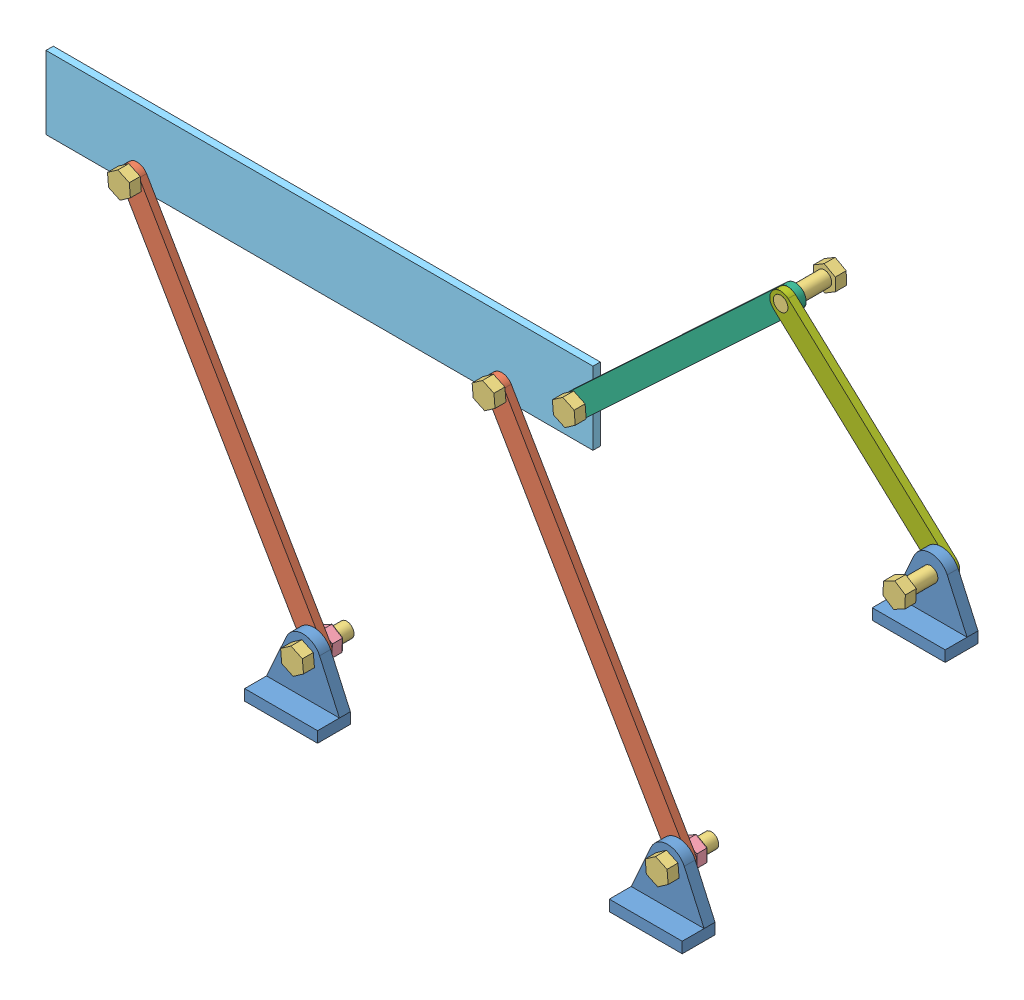
SolidWorks assembly 筛子, configuration 默认. Lengths in mm.
Overall size (259.58 165.17 28).
20 component instances, 7 part files, 39 mates.
Components (placement in the parent):
- 支座4-1: 支座4 [默认] at (-4.9178 3.6602 0) size (20 18 9)
- 杆100-1: 杆100 [默认] at (-31.141 48.5122 -2) x (-0.504726 0.86328 0) z (0 0 1) size (106 6 2)
- 螺钉4,12-1: 螺钉4,12 [默认] at (-4.9178 3.6602 3) size (6.28 6.9 15)
- 螺母4-1: 螺母4 [默认] at (-4.9178 3.6602 -2) x (-0.923728 -0.383049 0) z (0 0 -1) size (6.9 6.3 3)
- 支座4-2: 支座4 [默认] at (95.0822 3.6602 0) size (20 18 9)
- 螺钉4,12-2: 螺钉4,12 [默认] at (95.0822 3.6602 3) size (6.28 6.9 15)
- 螺母4-2: 螺母4 [默认] at (95.0822 3.6602 -2) x (-0.909504 -0.415695 0) z (0 0 -1) size (6.9 6.3 3)
- 杆100-2: 杆100 [默认] at (70.8328 45.1362 -2) x (0.504726 -0.86328 0) z (0 0 1) size (106 6 2)
- 平台-1: 平台 [默认] at (-5.3904 96.9882 -2) x (-1 0 0) z (0 0 -1) size (150 20 2)
- 螺钉4,12-3: 螺钉4,12 [默认] at (44.6096 89.9882 0) size (6.28 6.9 15)
- 螺母4-3: 螺母4 [默认] at (44.6096 89.9882 -4) x (0.120808 -0.992676 0) z (0 0 -1) size (6.9 6.3 3)
- 螺钉4,12-4: 螺钉4,12 [默认] at (-55.3904 89.9882 0) size (6.28 6.9 15)
- 螺母4-4: 螺母4 [默认] at (-55.3904 89.9882 -4) x (-0.923728 -0.383049 0) z (0 0 -1) size (6.9 6.3 3)
- 杆80-1: 杆80 [默认] at (98.5457 126.807 -2) x (0.73092 0.682463 0) z (0 0 1) size (86 6 2)
- 螺钉4,12-5: 螺钉4,12 [默认] at (66.6096 96.9882 0) size (6.28 6.9 15)
- 螺母4-5: 螺母4 [默认] at (66.6096 96.9882 -4) x (0.120808 -0.992676 0) z (0 0 -1) size (6.9 6.3 3)
- 杆60-1: 杆60 [默认] at (157.9979 121.2367 0) x (0.735185 -0.677867 0) z (0 0 1) size (66 6 2)
- 螺钉4,12-6: 螺钉4,12 [默认] at (125.0832 151.5852 -10) x (0.9945 0.104738 0) z (0 0 -1) size (6.28 6.9 15)
- 支座4-3: 支座4 [默认] at (169.1943 110.9132 2) size (20 18 9)
- 螺钉4,12-7: 螺钉4,12 [默认] at (169.1943 110.9132 12) x (0.990726 -0.135875 0) z (0 0 1) size (6.28 6.9 15)
Mates (geometry in assembly coordinates):
- 重合1: coincident: plane of 支座4-1 through (-4.9178 3.6602 0) normal (0 0 -1); plane of 杆100-1 through (-4.9178 3.6602 0) normal (0 0 1)
- 同心1: concentric: cylinder of 支座4-1 through (-4.9178 3.6602 3) axis (0 0 -1) radius 2; cylinder of 杆100-1 through (-4.9178 3.6602 0) axis (0 0 -1) radius 2
- 重合2: coincident: plane of 支座4-1 through (-4.9178 3.6602 3) normal (0 0 1); plane of 螺钉4,12-1 through (-4.6186 0.2091 3) normal (0 0 -1)
- 同心2: concentric: cylinder of 支座4-1 through (-4.9178 3.6602 3) axis (0 0 -1) radius 2; cylinder of 螺钉4,12-1 through (-4.9178 3.6602 -9) axis (0 0 1) radius 2
- 重合3: coincident: plane of 杆100-1 through (-4.9178 3.6602 -2) normal (0 0 -1); plane of 螺母4-1 through (-5.0386 0.1982 -2) normal (0 0 1)
- 同心3: concentric: cylinder of 螺钉4,12-1 through (-4.9178 3.6602 -9) axis (0 0 1) radius 2; cylinder of 螺母4-1 through (-4.9178 3.6602 -5) axis (0 0 1) radius 2
- 重合6: coincident: plane of 支座4-1; plane of 支座4-2
- 重合7: coincident: plane of 支座4-1 through (-4.9178 3.6602 0) normal (0 0 -1); plane of 支座4-2 through (95.0822 3.6602 0) normal (0 0 -1)
- 距离1: distance = 100 mm: plane of 支座4-1; plane of 支座4-2
- 重合9: coincident: plane of 支座4-2 through (95.0822 3.6602 3) normal (0 0 1); plane of 螺钉4,12-2 through (95.3814 0.2091 3) normal (0 0 -1)
- 同心4: concentric: cylinder of 支座4-2 through (95.0822 3.6602 3) axis (0 0 -1) radius 2; cylinder of 螺钉4,12-2 through (95.0822 3.6602 -9) axis (0 0 1) radius 2
- 重合10: coincident: plane of 支座4-2 through (95.0822 3.6602 0) normal (0 0 -1); plane of 杆100-2 through (108.528 102.7522 0) normal (0 0 1)
- 同心5: concentric: cylinder of 螺钉4,12-2 through (95.0822 3.6602 -9) axis (0 0 1) radius 2; cylinder of 杆100-2 through (95.0822 3.6602 0) axis (0 0 -1) radius 2
- 同心6: concentric: cylinder of 螺钉4,12-2 through (95.0822 3.6602 -9) axis (0 0 1) radius 2; cylinder of 螺母4-2 through (95.0822 3.6602 -5) axis (0 0 1) radius 2
- 重合12: coincident: plane of 杆100-1 through (-4.9178 3.6602 -2) normal (0 0 -1); plane of 平台-1 through (58.528 -8.0944 -2) normal (0 0 1)
- 同心9: concentric: cylinder of 杆100-2 through (108.528 102.7522 0) axis (0 0 -1) radius 2; cylinder of 螺钉4,12-3 through (108.528 102.7522 -12) axis (0 0 1) radius 2
- 重合13: coincident: plane of 杆100-2 through (108.528 102.7522 0) normal (0 0 1); plane of 螺钉4,12-3 through (108.8272 99.301 0) normal (0 0 -1)
- 同心10: concentric: cylinder of 平台-1 through (108.528 102.7522 -4) axis (0 0 1) radius 2; cylinder of 螺钉4,12-3 through (108.528 102.7522 -12) axis (0 0 1) radius 2
- 重合14: coincident: plane of 平台-1 through (58.528 -8.0944 -4) normal (0 0 -1); plane of 螺母4-3 through (111.8303 101.7057 -4) normal (0 0 1)
- 同心11: concentric: cylinder of 螺钉4,12-3 through (108.528 102.7522 -12) axis (0 0 1) radius 2; cylinder of 螺母4-3 through (108.528 102.7522 -7) axis (0 0 1) radius 2
- 重合15: coincident: plane of 杆100-1 through (-4.9178 3.6602 0) normal (0 0 1); plane of 螺钉4,12-4 through (8.8272 99.301 0) normal (0 0 -1)
- 同心12: concentric: cylinder of 杆100-1 through (8.528 102.7522 0) axis (0 0 -1) radius 2; cylinder of 螺钉4,12-4 through (8.528 102.7522 -12) axis (0 0 1) radius 2
- 同心13: concentric: cylinder of 平台-1 through (8.528 102.7522 -4) axis (0 0 1) radius 2; cylinder of 螺钉4,12-4 through (8.528 102.7522 -12) axis (0 0 1) radius 2
- 重合16: coincident: plane of 平台-1 through (58.528 -8.0944 -4) normal (0 0 -1); plane of 螺母4-4 through (8.4072 99.2902 -4) normal (0 0 1)
- 同心14: concentric: cylinder of 螺钉4,12-4 through (8.528 102.7522 -12) axis (0 0 1) radius 2; cylinder of 螺母4-4 through (8.528 102.7522 -7) axis (0 0 1) radius 2
- 重合17: coincident: plane of 平台-1 through (58.528 -8.0944 -2) normal (0 0 1); plane of 杆80-1 through (130.528 109.7522 -2) normal (0 0 -1)
- 重合18: coincident: plane of 杆80-1 through (130.528 109.7522 0) normal (0 0 1); plane of 螺钉4,12-5 through (130.8272 106.301 0) normal (0 0 -1)
- 同心15: concentric: cylinder of 杆80-1 through (130.528 109.7522 0) axis (0 0 -1) radius 2; cylinder of 螺钉4,12-5 through (130.528 109.7522 -12) axis (0 0 1) radius 2
- 同心16: concentric: cylinder of 平台-1 through (130.528 109.7522 -4) axis (0 0 1) radius 2; cylinder of 螺钉4,12-5 through (130.528 109.7522 -12) axis (0 0 1) radius 2
- 同心17: concentric: cylinder of 螺钉4,12-5 through (130.528 109.7522 -12) axis (0 0 1) radius 2; cylinder of 螺母4-5 through (130.528 109.7522 -7) axis (0 0 1) radius 2
- 重合19: coincident: plane of 平台-1 through (58.528 -8.0944 -4) normal (0 0 -1); plane of 螺母4-5 through (133.8303 108.7057 -4) normal (0 0 1)
- 同心18: concentric: cylinder of 杆80-1 through (184.64 168.6749 0) axis (0 0 -1) radius 2; cylinder of 螺钉4,12-6 through (184.64 168.6749 2) axis (0 0 -1) radius 2
- 同心19: concentric: cylinder of 杆60-1 through (184.64 168.6749 2) axis (0 0 -1) radius 2; cylinder of 螺钉4,12-6 through (184.64 168.6749 2) axis (0 0 -1) radius 2
- 重合24: coincident: plane of 螺母4-2 through (95.0847 0.1961 -2) normal (0 0 1); plane of 杆100-2 through (108.528 102.7522 -2) normal (0 0 -1)
- 重合25: coincident: plane of 杆60-1 through (184.64 168.6749 2) normal (0 0 1); plane of 支座4-3 through (169.3382 110.659 2) normal (0 0 -1)
- 同心21: concentric: cylinder of 支座4-3 through (169.3382 110.659 5) axis (0 0 -1) radius 2; cylinder of 螺钉4,12-7 through (169.3382 110.659 0) axis (0 0 1) radius 2
- 同心22: concentric: cylinder of 杆60-1 through (169.3382 110.659 2) axis (0 0 -1) radius 2; cylinder of 螺钉4,12-7 through (169.3382 110.659 0) axis (0 0 1) radius 2
- 重合40: coincident: plane of 杆60-1 through (184.64 168.6749 0) normal (0 0 -1); plane of 螺钉4,12-7 through (169.3382 110.659 0) normal (0 0 -1)
- 重合43: coincident: plane of 杆60-1 through (184.64 168.6749 2) normal (0 0 1); plane of 螺钉4,12-6 through (184.64 168.6749 2) normal (0 0 1)
